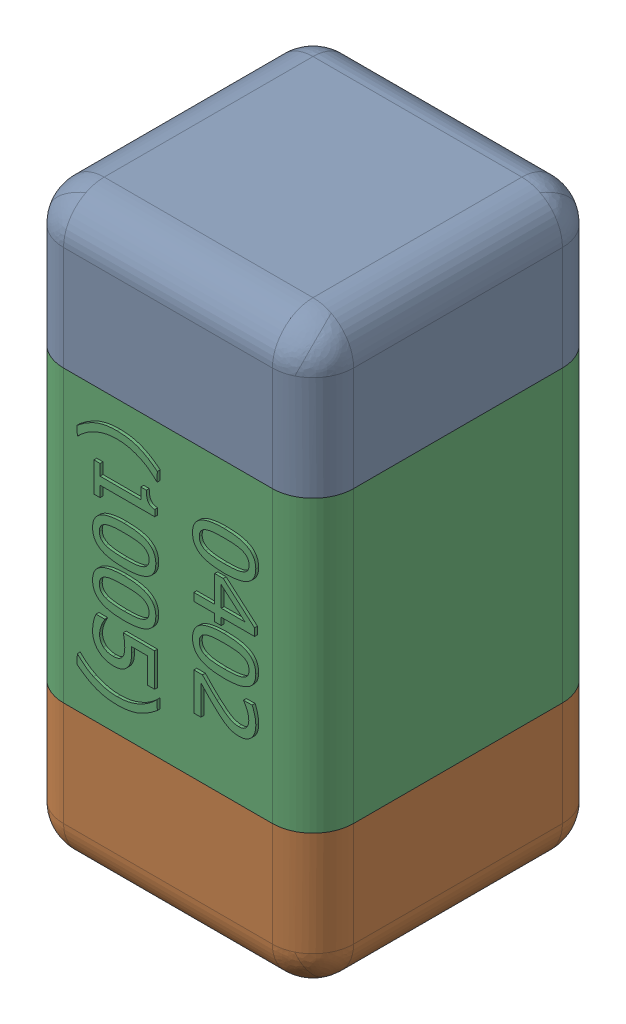
SolidWorks assembly C2, configuration Standard. Lengths in mm.
Overall size (0.51 1.01 0.51).
4 component instances, 3 part files, 0 mates.
Components (placement in the parent):
- C2-subassembly-1-1: C2-subassembly-1 [Standard] at (-5.7 -1.3001 0) x (0 -1 0) z (0 0 1) size (1.01 0.51 0.51)
  - User Library-0402_Cap-1: User Library-0402_Cap [Standard] at origin size (0.26 0.51 0.51)
  - User Library-0402_Cap-1-1: User Library-0402_Cap-1 [Standard] at origin size (0.26 0.5 0.51)
  - User Library-0402_Cap-2-1: User Library-0402_Cap-2 [Standard] at origin size (0.5 0.5 0.51)
